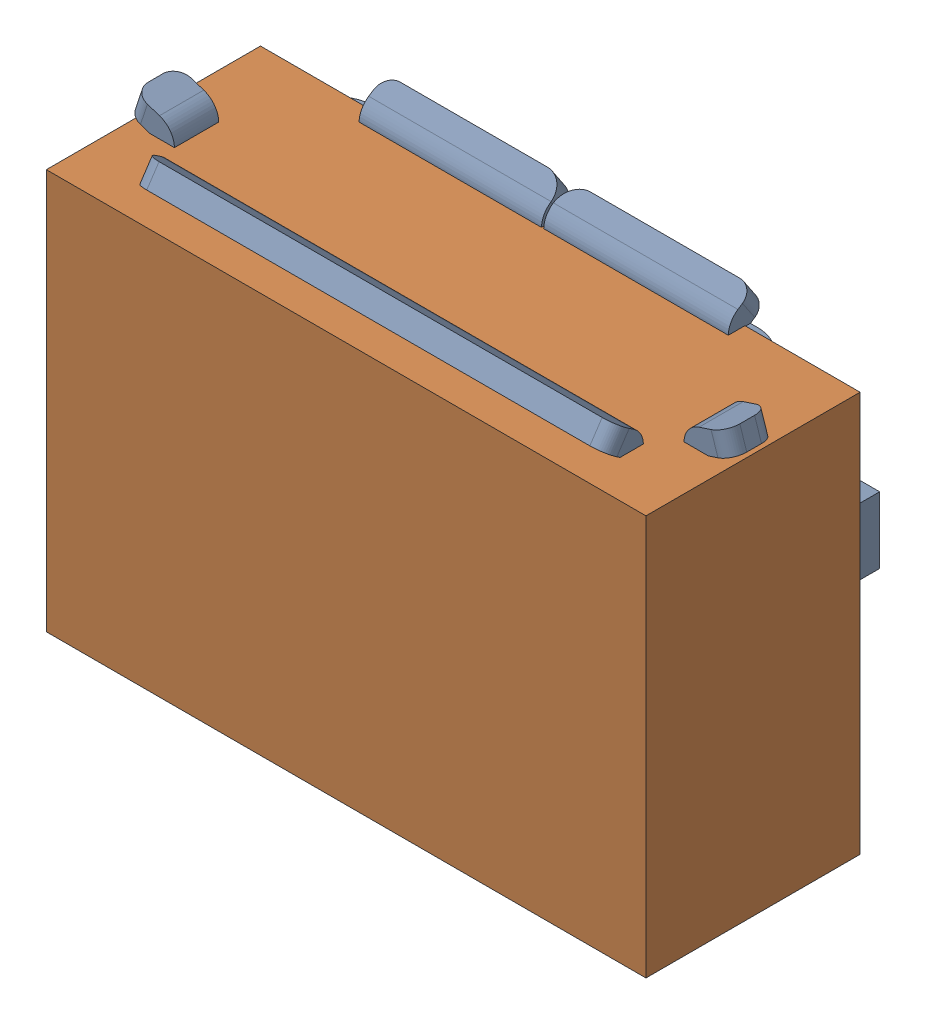
SolidWorks assembly CN1, configuration Default. Lengths in mm.
Overall size (8.2 5.81 3.57).
7 component instances, 4 part files, 0 mates.
Components (placement in the parent):
- MOLEX_105017-0001-1: MOLEX_105017-0001 [Default] at (9.2709 48.6919 1.15) x (-1 0 0) z (0 1 0) size (8.2 3.3 5.4)
  - Open CASCADE STEP translator 6.8 2.60.1.1-1: Open CASCADE STEP translator 6.8 2.60.1.1 [Default] at origin size (8.2 3.3 5.4)
  - Open CASCADE STEP translator 6.8 2.60.1.2-1: Open CASCADE STEP translator 6.8 2.60.1.2 [Default] at origin (suppressed, hidden)
- 1088890144-1: 1088890144 [Default] at (9.271 48.342 0) size (8.12 5.42 2.9)
  - Extruded-43-1: Extruded-43 [Default] at origin size (8.12 5.42 2.9)
- 1088890280-1: 1088890280 [Default] at (9.271 47.992 0) size (8 4.6 2.9)
  - Extruded-44-1: Extruded-44 [Default] at origin size (8 4.6 2.9)
